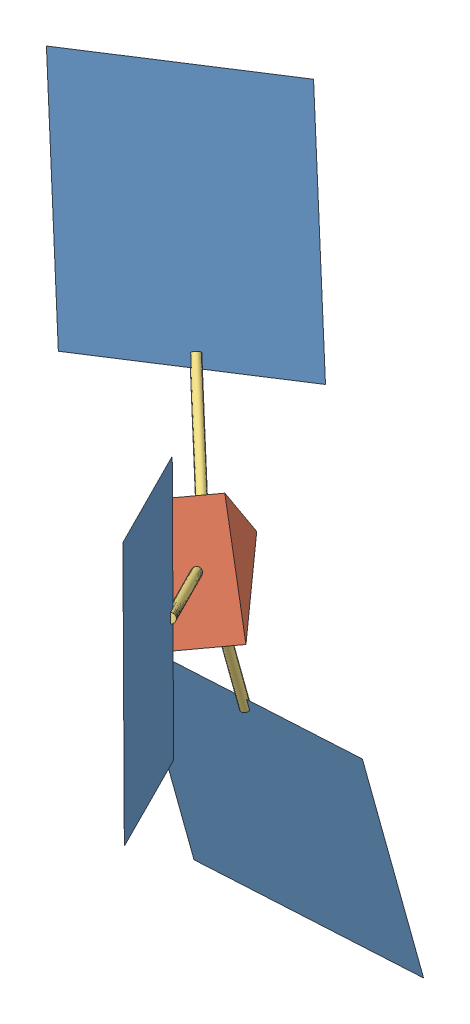
SolidWorks assembly Sail, configuration Default. Lengths in mm.
Overall size (2106.91 2830.37 2615.35).
7 component instances, 3 part files, 16 mates.
Components (placement in the parent):
- panel-2: panel [Default] at (455.5275 91.3046 775.0784) x (0.236398 -0.944008 0.230141) z (0.801565 0.055595 -0.595317) size (1000 1000 0)
- panel-3: panel [Default] at (-797.8838 498.445 -494.5815) x (0.568414 -0.641599 0.515031) z (-0.749886 -0.661557 0.003478) size (1000 1000 0)
- panel-4: panel [Default] at (-151.7599 -1349.2655 -269.2374) x (0.019224 -0.966804 -0.254795) z (-0.034234 0.254056 -0.966583) size (1000 1000 0)
- triangle-1: triangle [Default] at (-106.1145 -276.8197 192.6411) x (0.339273 -0.928612 0.150247) z (0.763731 0.178667 -0.620317) size (500 433.01 250)
- pipe-1: pipe [Default] at (282.2896 -81.0219 525.7267) x (0.236398 -0.944008 0.230141) z (-0.54919 -0.325205 -0.769826) size (38.1 38.1 609.6)
- pipe-2: pipe [Default] at (-76.888 -956.665 -168.6977) x (-0.999229 -0.027304 0.028214) z (-0.019224 0.966804 0.254795) size (38.1 38.1 609.6)
- pipe-4: pipe [Default] at (-475.1521 133.41 -345.0692) x (-0.338491 0.388192 0.857165) z (0.568414 -0.641599 0.515031) size (38.1 38.1 609.6)
Mates (geometry in assembly coordinates):
- Coincident9: coincident: line of panel-3 through (-621.1857 301.4054 124.0153) axis (0.338491 -0.388192 -0.857165); plane of pipe-4 through (-446.2767 100.8168 -318.9057) normal (-0.568414 0.641599 -0.515031)
- Coincident10: coincident aligned: plane of panel-3 through (-797.8838 498.445 -494.5815) normal (0.749886 0.661557 -0.003478); plane of pipe-4 through (-446.2771 100.8164 -318.9057) normal (0.749886 0.661557 -0.003478)
- Coincident20: coincident: line of panel-2 through (131.7271 392.2881 367.2034) axis (0.236398 -0.944008 0.230141); plane of pipe-1 through (254.3908 -97.5423 486.6196) normal (0.54919 0.325205 0.769826)
- Coincident21: coincident aligned: plane of panel-2 through (455.5283 91.3047 775.0778) normal (0.801565 0.055595 -0.595317); plane of pipe-1 through (254.3904 -97.5423 486.6199) normal (0.801565 0.055595 -0.595317)
- Coincident24: coincident: line of panel-4 through (-554.1337 -920.5652 -142.3078) axis (0.999229 0.027304 -0.028214); plane of pipe-2 through (-77.8646 -907.5513 -155.7541) normal (0.019224 -0.966804 -0.254795)
- Coincident25: coincident aligned: plane of panel-4 through (-151.7599 -1349.2655 -269.2374) normal (0.034234 -0.254056 0.966583); plane of pipe-2 through (-96.8999 -908.0713 -155.2171) normal (0.034234 -0.254056 0.966583)
- Coincident26: coincident: point of triangle-1
- Coincident33: coincident anti-aligned: plane of triangle-1 through (-128.6472 -257.7086 -31.1064) normal (-0.568414 0.641599 -0.515031); plane of pipe-4 through (-128.6472 -257.7086 -31.1064) normal (0.568414 -0.641599 0.515031)
- Concentric7: concentric aligned: cylinder of triangle-1 through (-128.6472 -257.7086 -31.1064) axis (-0.568414 0.641599 -0.515031) radius 19.05; cylinder of pipe-4 through (-128.6472 -257.7086 -31.1064) axis (-0.568414 0.641599 -0.515031) radius 19.05
- Coincident34: coincident anti-aligned: plane of triangle-1 through (-88.607 -367.3013 -13.3745) normal (0.019224 -0.966804 -0.254795); plane of pipe-2 through (-88.607 -367.3013 -13.3745) normal (-0.019224 0.966804 0.254795)
- Concentric8: concentric aligned: cylinder of triangle-1 through (-88.607 -367.3013 -13.3745) axis (0.019224 -0.966804 -0.254795) radius 19.05; cylinder of pipe-2 through (-88.607 -367.3013 -13.3745) axis (0.019224 -0.966804 -0.254795) radius 19.05
- Coincident35: coincident anti-aligned: plane of triangle-1 through (-52.4964 -279.2669 56.4407) normal (0.54919 0.325205 0.769826); plane of pipe-1 through (-52.4964 -279.2669 56.4407) normal (-0.54919 -0.325205 -0.769826)
- Concentric9: concentric aligned: cylinder of triangle-1 through (-52.4964 -279.2669 56.4407) axis (0.54919 0.325205 0.769826) radius 19.05; cylinder of pipe-1 through (-52.4964 -279.2669 56.4407) axis (0.54919 0.325205 0.769826) radius 19.05
- Lock1: lock: unknown of panel-4; unknown of pipe-2
- Lock2: lock: unknown of panel-3; unknown of pipe-4
- Lock3: lock: unknown of panel-2; unknown of pipe-1
